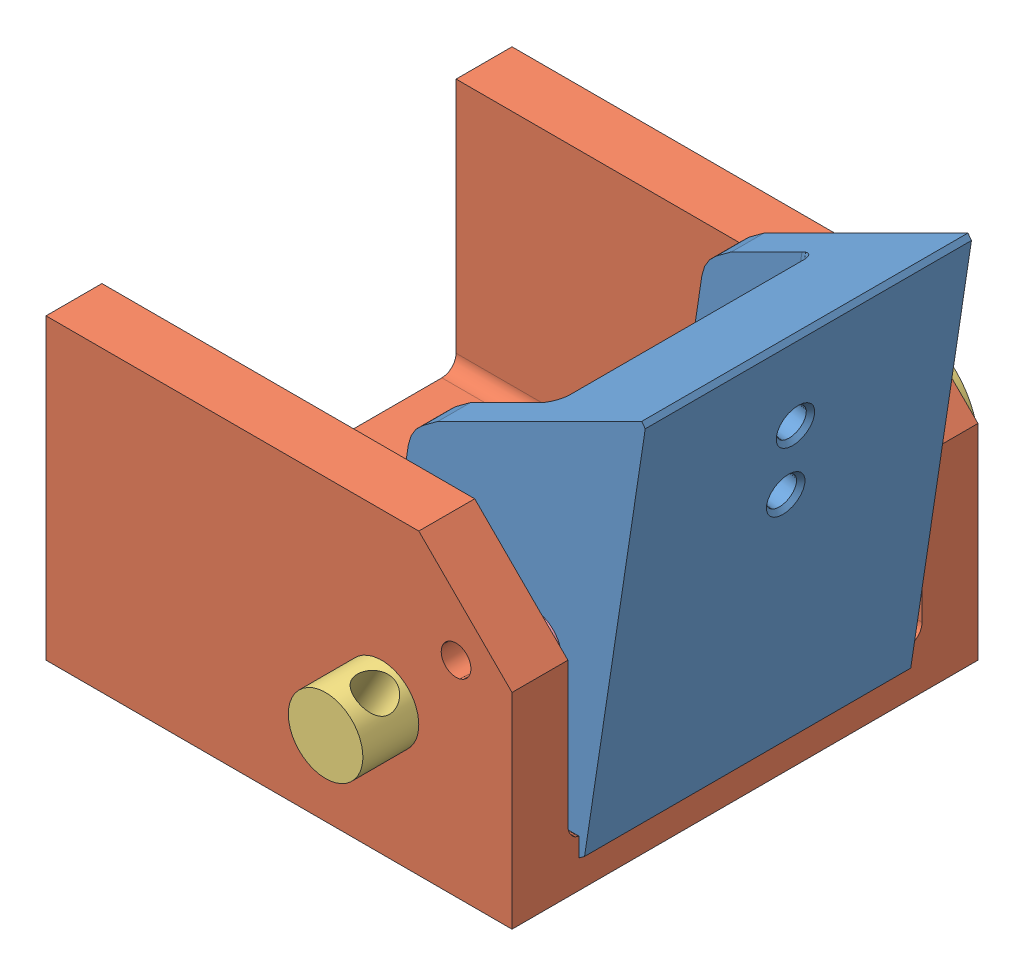
SolidWorks assembly Assembly_V1, configuration Default. Lengths in mm.
Overall size (28.58 25.17 31).
7 component instances, 5 part files, 9 mates.
Components (placement in the parent):
- Swing piece better redesign v2-1: Swing piece better redesign v2 [Default] at (10.5166 16.001 11.8718) x (0.988728 -0.14972 0) z (0 0 1) size (11.5 22.34 17.5)
- Base better redesign-1: Base better redesign [Default] at (1.9122 2.865 20.4718) x (1 0 0) z (0 -1 0) size (25 25 16)
- Hinge mcmaster 4mm-1: Hinge mcmaster 4mm [93217A290] at (7.4122 7.365 129.9718) x (0.866515 -0.49915 0) z (0 0 1) size (8 8 31)
- Pin mcmaster_v2-1: Pin mcmaster_v2 [98378A149] at (11.966 10.7211 -18.0282) x (-0.894491 0.447087 0) z (0 0 -1) size (3 3 7)
- 9271K88_Torsion Spring-1: 9271K88_Torsion Spring [9271K88] at (7.691 7.499 23.983) x (0.159653 -0.022827 -0.986909) z (-0.95932 -0.239394 -0.149653) size (4.03 5.49 38.1) (hidden)
- 9271K88_Torsion Spring-3: 9271K88_Torsion Spring [9271K88] at (7.1421 7.2576 15.5875) x (-0.070231 -0.093274 -0.99316) z (-0.995192 0.074684 0.06336) size (4.03 5.49 38.1) (hidden)
- Pin mcmaster_v2-3: Pin mcmaster_v2 [98378A149] at (11.966 10.7211 58.9718) x (0.595621 -0.803266 0) z (0 0 1) size (3 3 7)
Mates (geometry in assembly coordinates):
- Concentric1: concentric anti-aligned: cylinder of Hinge mcmaster 4mm-1 through (7.4122 7.365 254.9718) axis (0 0 1) radius 2; cylinder of Base better redesign-1 through (7.4122 7.365 32.9718) axis (0 0 -1) radius 2
- Coincident2: coincident anti-aligned: plane of Base better redesign-1 through (-10.5878 0.365 7.9718) normal (0 0 -1); plane of Hinge mcmaster 4mm-1 through (9.4088 10.8311 7.9718) normal (0 0 1)
- Concentric2: concentric anti-aligned: cylinder of Swing piece better redesign v2-1 through (7.4122 7.365 29.3718) axis (0 0 -1) radius 2; cylinder of Hinge mcmaster 4mm-1 through (7.4122 7.365 254.9718) axis (0 0 1) radius 2
- Distance1: distance = 0.6 mm anti-aligned: plane of Swing piece better redesign v2-1 through (10.5166 16.001 29.3718) normal (0 0 1); plane of Base better redesign-1 through (-10.5878 16.365 29.9718) normal (0 0 -1)
- Concentric4: concentric anti-aligned: cylinder of Swing piece better redesign v2-1 through (11.966 10.7211 18.8718) axis (0 0 -1) radius 1.5; cylinder of Pin mcmaster_v2-1 through (11.966 10.7211 15.9718) axis (0 0 1) radius 1.5
- Coincident5: coincident anti-aligned: plane of Base better redesign-1 through (-10.5878 16.365 10.9718) normal (0 0 1); plane of Pin mcmaster_v2-1 through (12.413 11.6155 10.9718) normal (0 0 -1)
- Tangent6: tangent anti-aligned: cylinder of Hinge mcmaster 4mm-1 through (7.4122 7.365 254.9718) axis (0 0 1) radius 2; face of 9271K88_Torsion Spring-1
- Concentric6: concentric anti-aligned: cylinder of Swing piece better redesign v2-1 through (11.966 10.7211 22.3718) axis (0 0 1) radius 1.5; cylinder of Pin mcmaster_v2-3 through (11.966 10.7211 24.9718) axis (0 0 -1) radius 1.5
- Coincident6: coincident anti-aligned: plane of Base better redesign-1 through (-10.5878 16.365 29.9718) normal (0 0 -1); plane of Pin mcmaster_v2-3 through (12.7692 11.3167 29.9718) normal (0 0 1)
